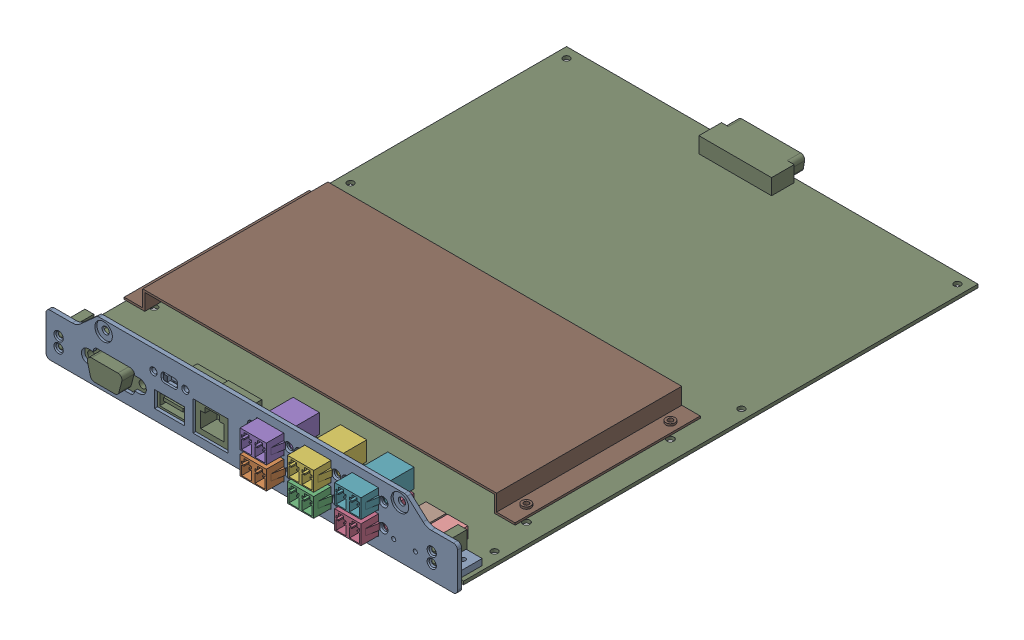
SolidWorks assembly User Library-fod-assy_asm_FOD-MODULE-ASSY_ASM, configuration Default. Lengths in mm.
Overall size (200 30 265.8).
10 component instances, 5 part files, 0 mates.
Components (placement in the parent):
- User Library-fod-assy_asm_FOD-IO-PANEL-1: User Library-fod-assy_asm_FOD-IO-PANEL [Default] at (0 -2.9 1) size (200 30 14)
- User Library-fod-assy_asm_CONN-LC-TYPE-SCREW-1: User Library-fod-assy_asm_CONN-LC-TYPE-SCREW [Default] at (109 12 11.3) x (-1 0 0) z (0 0 1) size (22 9.3 25.8)
- User Library-fod-assy_asm_CONN-LC-TYPE-SCREW-2: User Library-fod-assy_asm_CONN-LC-TYPE-SCREW [Default] at (132 12 11.3) x (-1 0 0) z (0 0 1) size (22 9.3 25.8)
- User Library-fod-assy_asm_CONN-LC-TYPE-SCREW-3: User Library-fod-assy_asm_CONN-LC-TYPE-SCREW [Default] at (155 12 11.3) x (-1 0 0) z (0 0 1) size (22 9.3 25.8)
- User Library-fod-assy_asm_CONN-LC-TYPE-SCREW-4: User Library-fod-assy_asm_CONN-LC-TYPE-SCREW [Default] at (109 23 11.3) x (-1 0 0) z (0 0 1) size (22 9.3 25.8)
- User Library-fod-assy_asm_CONN-LC-TYPE-SCREW-5: User Library-fod-assy_asm_CONN-LC-TYPE-SCREW [Default] at (132 23 11.3) x (-1 0 0) z (0 0 1) size (22 9.3 25.8)
- User Library-fod-assy_asm_CONN-LC-TYPE-SCREW-6: User Library-fod-assy_asm_CONN-LC-TYPE-SCREW [Default] at (155 23 11.3) x (-1 0 0) z (0 0 1) size (22 9.3 25.8)
- User Library-fod-assy_asm_FOD-MAIN-BD-1: User Library-fod-assy_asm_FOD-MAIN-BD [Default] at origin size (200 15.1 262)
- User Library-fod-assy_asm_SLIDE-SWITCH-1: User Library-fod-assy_asm_SLIDE-SWITCH [Default] at (60 14.5 -5) size (19 6 10.5)
- User Library-fod-assy_asm_FOD-BD-COVER-1: User Library-fod-assy_asm_FOD-BD-COVER [Default] at (100 7.6 -120) size (190 9 90)
